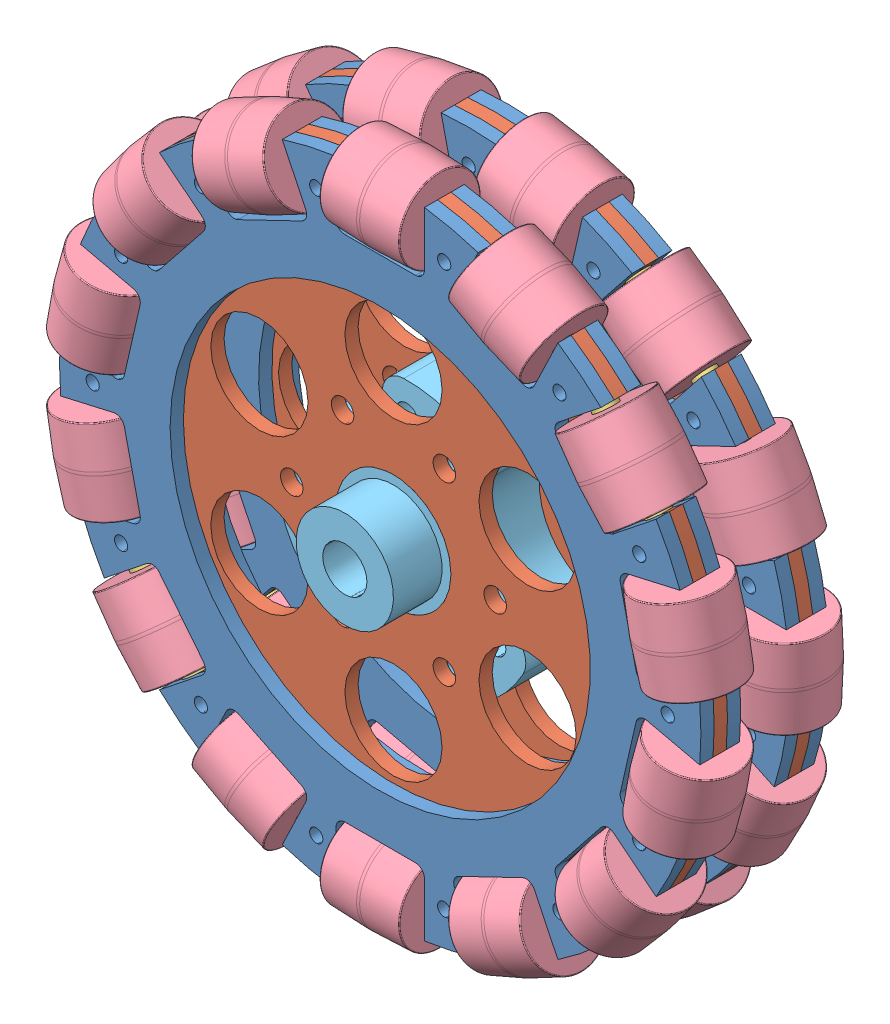
SolidWorks assembly 150mm全向轮-0320, configuration 默认. Lengths in mm.
Overall size (192.95 192.95 43.78).
63 component instances, 5 part files, 26 mates.
Components (placement in the parent):
- VJ_150全向轮外壁-0320-1: VJ_150全向轮外壁-0320 [默认] at (-10.4986 6.27 143.5) size (145 143.61 3)
- VJ_150全向轮内壁-0320-1: VJ_150全向轮内壁-0320 [默认] at (-10.4986 6.27 146.5) size (145 143.61 3)
- VJ_150全向轮外壁-0320-2: VJ_150全向轮外壁-0320 [默认] at (-10.4986 6.27 152.5) x (0.900969 0.433884 0) z (0 0 -1) size (145 143.61 3)
- VJ_150全向轮滚柱-0320-1: VJ_150全向轮滚柱-0320 [默认] at (-72.9604 32.8351 148) x (0.531534 -0.121319 -0.838304) z (-0.222521 -0.974928 0) size (5 5 24)
- VJ_150全向轮滚柱-0320-2: VJ_150全向轮滚柱-0320 [默认] at (-78.3009 3.1032 148) x (0.531534 0.121319 -0.838304) z (0.222521 -0.974928 0) size (5 5 24)
- VJ_150全向轮滚柱-0320-3: VJ_150全向轮滚柱-0320 [默认] at (-70.2123 -26.0015 148) x (0.426257 0.339929 -0.838304) z (0.62349 -0.781831 0) size (5 5 24)
- VJ_150全向轮滚柱-0320-4: VJ_150全向轮滚柱-0320 [默认] at (-50.2967 -48.7145 148) x (0.236555 0.491211 -0.838304) z (0.900969 -0.433884 0) size (5 5 24)
- VJ_150全向轮滚柱-0320-5: VJ_150全向轮滚柱-0320 [默认] at (-22.4986 -60.537 148) x (0 0.545203 -0.838304) z (1 0 0) size (5 5 24)
- VJ_150全向轮滚柱-0320-6: VJ_150全向轮滚柱-0320 [默认] at (7.6763 -59.1277 148) x (-0.236555 0.491211 -0.838304) z (0.900969 0.433884 0) size (5 5 24)
- VJ_150全向轮滚柱-0320-7: VJ_150全向轮滚柱-0320 [默认] at (34.2514 -44.7655 148) x (-0.426257 0.339929 -0.838304) z (0.62349 0.781831 0) size (5 5 24)
- VJ_150全向轮滚柱-0320-8: VJ_150全向轮滚柱-0320 [默认] at (51.9632 -20.2951 148) x (-0.531534 0.121319 -0.838304) z (0.222521 0.974928 0) size (5 5 24)
- VJ_150全向轮滚柱-0320-9: VJ_150全向轮滚柱-0320 [默认] at (57.3037 9.4368 148) x (-0.531534 -0.121319 -0.838304) z (-0.222521 0.974928 0) size (5 5 24)
- VJ_150全向轮滚柱-0320-10: VJ_150全向轮滚柱-0320 [默认] at (49.2151 38.5415 148) x (-0.426257 -0.339929 -0.838304) z (-0.62349 0.781831 0) size (5 5 24)
- VJ_150全向轮滚柱-0320-11: VJ_150全向轮滚柱-0320 [默认] at (29.2995 61.2544 148) x (-0.236555 -0.491211 -0.838304) z (-0.900969 0.433884 0) size (5 5 24)
- VJ_150全向轮滚柱-0320-12: VJ_150全向轮滚柱-0320 [默认] at (1.5014 73.077 148) x (0 -0.545203 -0.838304) z (-1 0 0) size (5 5 24)
- VJ_150全向轮滚柱-0320-13: VJ_150全向轮滚柱-0320 [默认] at (-28.6734 71.6676 148) x (0.236555 -0.491211 -0.838304) z (-0.900969 -0.433884 0) size (5 5 24)
- VJ_150全向轮滚柱-0320-14: VJ_150全向轮滚柱-0320 [默认] at (-55.2485 57.3055 148) x (0.426257 -0.339929 -0.838304) z (-0.62349 -0.781831 0) size (5 5 24)
- VJ_150全向轮小轮-0320-1: VJ_150全向轮小轮-0320 [默认] at (-75.6306 -8.596 148) x (0.950484 0.216942 -0.222521) z (0.222521 -0.974928 0) size (18.99 18.99 18)
- VJ_150全向轮小轮-0320-2: VJ_150全向轮小轮-0320 [默认] at (-62.7304 -35.3835 148) x (0.762229 0.607858 -0.222521) z (0.62349 -0.781831 0) size (18.99 18.99 18)
- VJ_150全向轮小轮-0320-3: VJ_150全向轮小轮-0320 [默认] at (-39.4851 -53.9211 148) x (0.423005 0.87838 -0.222521) z (0.900969 -0.433884 0) size (18.99 18.99 18)
- VJ_150全向轮小轮-0320-4: VJ_150全向轮小轮-0320 [默认] at (-10.4986 -60.537 148) x (0 0.974928 -0.222521) z (1 0 0) size (18.99 18.99 18)
- VJ_150全向轮小轮-0320-5: VJ_150全向轮小轮-0320 [默认] at (18.4879 -53.9211 148) x (-0.423005 0.87838 -0.222521) z (0.900969 0.433884 0) size (18.99 18.99 18)
- VJ_150全向轮小轮-0320-6: VJ_150全向轮小轮-0320 [默认] at (41.7333 -35.3835 148) x (-0.762229 0.607858 -0.222521) z (0.62349 0.781831 0) size (18.99 18.99 18)
- VJ_150全向轮小轮-0320-7: VJ_150全向轮小轮-0320 [默认] at (54.6335 -8.596 148) x (-0.950484 0.216942 -0.222521) z (0.222521 0.974928 0) size (18.99 18.99 18)
- VJ_150全向轮小轮-0320-8: VJ_150全向轮小轮-0320 [默认] at (54.6335 21.136 148) x (-0.950484 -0.216942 -0.222521) z (-0.222521 0.974928 0) size (18.99 18.99 18)
- VJ_150全向轮小轮-0320-9: VJ_150全向轮小轮-0320 [默认] at (41.7333 47.9235 148) x (-0.762229 -0.607858 -0.222521) z (-0.62349 0.781831 0) size (18.99 18.99 18)
- VJ_150全向轮小轮-0320-10: VJ_150全向轮小轮-0320 [默认] at (18.4879 66.461 148) x (-0.423005 -0.87838 -0.222521) z (-0.900969 0.433884 0) size (18.99 18.99 18)
- VJ_150全向轮小轮-0320-11: VJ_150全向轮小轮-0320 [默认] at (-10.4986 73.077 148) x (0 -0.974928 -0.222521) z (-1 0 0) size (18.99 18.99 18)
- VJ_150全向轮小轮-0320-12: VJ_150全向轮小轮-0320 [默认] at (-39.4851 66.461 148) x (0.423005 -0.87838 -0.222521) z (-0.900969 -0.433884 0) size (18.99 18.99 18)
- VJ_150全向轮小轮-0320-13: VJ_150全向轮小轮-0320 [默认] at (-62.7304 47.9235 148) x (0.762229 -0.607858 -0.222521) z (-0.62349 -0.781831 0) size (18.99 18.99 18)
- VJ_150全向轮小轮-0320-14: VJ_150全向轮小轮-0320 [默认] at (-75.6306 21.136 148) x (0.950484 -0.216942 -0.222521) z (-0.222521 -0.974928 0) size (18.99 18.99 18)
- VJ_150全向轮联轴-0320-1: VJ_150全向轮联轴-0320 [默认] at (-10.4986 6.27 129.5) x (0.965926 -0.258819 0) z (0 0 1) size (58.57 53.07 35)
- VJ_150全向轮外壁-0320-3: VJ_150全向轮外壁-0320 [默认] at (-10.4986 6.27 132.5) x (-0.433884 0.900969 0) z (0 0 -1) size (145 143.61 3)
- VJ_150全向轮内壁-0320-2: VJ_150全向轮内壁-0320 [默认] at (-10.4986 6.27 126.5) x (0 1 0) z (0 0 1) size (145 143.61 3)
- VJ_150全向轮外壁-0320-4: VJ_150全向轮外壁-0320 [默认] at (-10.4986 6.27 123.5) x (0 1 0) z (0 0 1) size (145 143.61 3)
- VJ_150全向轮滚柱-0320-15: VJ_150全向轮滚柱-0320 [默认] at (-37.0637 68.7318 128) x (-0.216942 0.950484 -0.222521) z (0.974928 0.222521 0) size (5 5 24)
- VJ_150全向轮滚柱-0320-16: VJ_150全向轮滚柱-0320 [默认] at (-61.5341 51.02 128) x (-0.607858 0.762229 -0.222521) z (0.781831 0.62349 0) size (5 5 24)
- VJ_150全向轮滚柱-0320-17: VJ_150全向轮滚柱-0320 [默认] at (-75.8962 24.4448 128) x (-0.87838 0.423005 -0.222521) z (0.433884 0.900969 0) size (5 5 24)
- VJ_150全向轮滚柱-0320-18: VJ_150全向轮滚柱-0320 [默认] at (-77.3056 -5.73 128) x (-0.974928 0 -0.222521) z (0 1 0) size (5 5 24)
- VJ_150全向轮滚柱-0320-19: VJ_150全向轮滚柱-0320 [默认] at (-65.483 -33.5281 128) x (-0.87838 -0.423005 -0.222521) z (-0.433884 0.900969 0) size (5 5 24)
- VJ_150全向轮滚柱-0320-20: VJ_150全向轮滚柱-0320 [默认] at (-42.7701 -53.4437 128) x (-0.607858 -0.762229 -0.222521) z (-0.781831 0.62349 0) size (5 5 24)
- VJ_150全向轮滚柱-0320-21: VJ_150全向轮滚柱-0320 [默认] at (-13.6654 -61.5323 128) x (-0.216942 -0.950484 -0.222521) z (-0.974928 0.222521 0) size (5 5 24)
- VJ_150全向轮滚柱-0320-22: VJ_150全向轮滚柱-0320 [默认] at (16.0665 -56.1918 128) x (0.216942 -0.950484 -0.222521) z (-0.974928 -0.222521 0) size (5 5 24)
- VJ_150全向轮滚柱-0320-23: VJ_150全向轮滚柱-0320 [默认] at (40.5369 -38.48 128) x (0.607858 -0.762229 -0.222521) z (-0.781831 -0.62349 0) size (5 5 24)
- VJ_150全向轮滚柱-0320-24: VJ_150全向轮滚柱-0320 [默认] at (54.8991 -11.9049 128) x (0.87838 -0.423005 -0.222521) z (-0.433884 -0.900969 0) size (5 5 24)
- VJ_150全向轮滚柱-0320-25: VJ_150全向轮滚柱-0320 [默认] at (56.3084 18.27 128) x (0.974928 0 -0.222521) z (0 -1 0) size (5 5 24)
- VJ_150全向轮滚柱-0320-26: VJ_150全向轮滚柱-0320 [默认] at (44.4859 46.0681 128) x (0.87838 0.423005 -0.222521) z (0.433884 -0.900969 0) size (5 5 24)
- VJ_150全向轮滚柱-0320-27: VJ_150全向轮滚柱-0320 [默认] at (21.7729 65.9837 128) x (0.607858 0.762229 -0.222521) z (0.781831 -0.62349 0) size (5 5 24)
- VJ_150全向轮滚柱-0320-28: VJ_150全向轮滚柱-0320 [默认] at (-7.3318 74.0723 128) x (0.216942 0.950484 -0.222521) z (0.974928 -0.222521 0) size (5 5 24)
- VJ_150全向轮小轮-0320-15: VJ_150全向轮小轮-0320 [默认] at (-25.3645 71.402 128) x (-0.217508 0.952966 -0.211058) z (0.974928 0.222521 0) size (18.99 18.99 18)
- VJ_150全向轮小轮-0320-16: VJ_150全向轮小轮-0320 [默认] at (-52.1521 58.5018 128) x (-0.609445 0.76422 -0.211058) z (0.781831 0.62349 0) size (18.99 18.99 18)
- VJ_150全向轮小轮-0320-17: VJ_150全向轮小轮-0320 [默认] at (-70.6896 35.2565 128) x (-0.880673 0.42411 -0.211058) z (0.433884 0.900969 0) size (18.99 18.99 18)
- VJ_150全向轮小轮-0320-18: VJ_150全向轮小轮-0320 [默认] at (-77.3056 6.27 128) x (-0.977474 0 -0.211058) z (0 1 0) size (18.99 18.99 18)
- VJ_150全向轮小轮-0320-19: VJ_150全向轮小轮-0320 [默认] at (-70.6896 -22.7165 128) x (-0.880673 -0.42411 -0.211058) z (-0.433884 0.900969 0) size (18.99 18.99 18)
- VJ_150全向轮小轮-0320-20: VJ_150全向轮小轮-0320 [默认] at (-52.1521 -45.9619 128) x (-0.609445 -0.76422 -0.211058) z (-0.781831 0.62349 0) size (18.99 18.99 18)
- VJ_150全向轮小轮-0320-21: VJ_150全向轮小轮-0320 [默认] at (-25.3645 -58.8621 128) x (-0.217508 -0.952966 -0.211058) z (-0.974928 0.222521 0) size (18.99 18.99 18)
- VJ_150全向轮小轮-0320-22: VJ_150全向轮小轮-0320 [默认] at (4.3674 -58.8621 128) x (0.217508 -0.952966 -0.211058) z (-0.974928 -0.222521 0) size (18.99 18.99 18)
- VJ_150全向轮小轮-0320-23: VJ_150全向轮小轮-0320 [默认] at (31.1549 -45.9619 128) x (0.609445 -0.76422 -0.211058) z (-0.781831 -0.62349 0) size (18.99 18.99 18)
- VJ_150全向轮小轮-0320-24: VJ_150全向轮小轮-0320 [默认] at (49.6925 -22.7165 128) x (0.880673 -0.42411 -0.211058) z (-0.433884 -0.900969 0) size (18.99 18.99 18)
- VJ_150全向轮小轮-0320-25: VJ_150全向轮小轮-0320 [默认] at (56.3084 6.27 128) x (0.977474 0 -0.211058) z (0 -1 0) size (18.99 18.99 18)
- VJ_150全向轮小轮-0320-26: VJ_150全向轮小轮-0320 [默认] at (49.6925 35.2565 128) x (0.880673 0.42411 -0.211058) z (0.433884 -0.900969 0) size (18.99 18.99 18)
- VJ_150全向轮小轮-0320-27: VJ_150全向轮小轮-0320 [默认] at (31.1549 58.5018 128) x (0.609445 0.76422 -0.211058) z (0.781831 -0.62349 0) size (18.99 18.99 18)
- VJ_150全向轮小轮-0320-28: VJ_150全向轮小轮-0320 [默认] at (4.3674 71.402 128) x (0.217508 0.952966 -0.211058) z (0.974928 -0.222521 0) size (18.99 18.99 18)
Mates (geometry in assembly coordinates):
- 同心1: concentric: circle of VJ_150全向轮内壁-0320-1; circle of VJ_150全向轮外壁-0320-2
- 同心2: concentric: circle of VJ_150全向轮外壁-0320-1; cylinder of VJ_150全向轮内壁-0320-1 through (-10.4986 6.27 146.5) axis (0 0 1) radius 13
- 重合1: coincident: plane of VJ_150全向轮外壁-0320-1 through (-72.6739 68.6437 146.5) normal (-0.62349 -0.781831 0); plane of VJ_150全向轮内壁-0320-1 through (-72.6739 68.6437 149.5) normal (-0.62349 -0.781831 0)
- 重合3: coincident: plane of VJ_150全向轮外壁-0320-1 through (-10.4986 6.27 146.5) normal (0 0 1); plane of VJ_150全向轮内壁-0320-1 through (-10.4986 6.27 146.5) normal (0 0 -1)
- 重合5: coincident: plane of VJ_150全向轮内壁-0320-1 through (-10.4986 6.27 149.5) normal (0 0 1); plane of VJ_150全向轮外壁-0320-2 through (-10.4986 6.27 149.5) normal (0 0 -1)
- 重合6: coincident: plane of VJ_150全向轮外壁-0320-1 through (-72.6739 68.6437 146.5) normal (-0.62349 -0.781831 0); plane of VJ_150全向轮外壁-0320-2 through (-72.6739 68.6437 149.5) normal (-0.62349 -0.781831 0)
- 同心3: concentric: cylinder of VJ_150全向轮外壁-0320-1 through (-72.9604 32.8351 148) axis (-0.222521 -0.974928 0) radius 2.5; cylinder of VJ_150全向轮滚柱-0320-1 through (-78.3009 9.4368 148) axis (0.222521 0.974928 0) radius 2.5
- 重合7: coincident: plane of VJ_150全向轮内壁-0320-1 through (-78.3009 9.4368 148) normal (0.222521 0.974928 0); plane of VJ_150全向轮滚柱-0320-1 through (-78.3009 9.4368 148) normal (-0.222521 -0.974928 0)
- 同心4: concentric: cylinder of VJ_150全向轮滚柱-0320-2 through (-72.9604 -20.2951 148) axis (-0.222521 0.974928 0) radius 2.5; cylinder of VJ_150全向轮小轮-0320-1 through (-77.6333 0.1784 148) axis (0.222521 -0.974928 0) radius 2.5
- 距离1: distance = 1 mm: plane of VJ_150全向轮小轮-0320-1 through (-77.6333 0.1784 148) normal (-0.222521 0.974928 0); plane of VJ_150全向轮内壁-0320-1 through (-98.03 -3.4513 149.5) normal (0.222521 -0.974928 0)
- 同心6: concentric: cylinder of VJ_150全向轮内壁-0320-1 through (1.0014 26.1886 146.5) axis (0 0 1) radius 2.55; cylinder of VJ_150全向轮联轴-0320-1 through (1.0014 26.1886 146.5) axis (0 0 -1) radius 2.5
- 重合9: coincident: plane of VJ_150全向轮内壁-0320-1 through (-10.4986 6.27 146.5) normal (0 0 -1); plane of VJ_150全向轮联轴-0320-1 through (-10.4986 6.27 146.5) normal (0 0 1)
- 同心7: concentric: circle of VJ_150全向轮外壁-0320-3; cylinder of VJ_150全向轮内壁-0320-2 through (-10.4986 6.27 126.5) axis (0 0 1) radius 13
- 同心8: concentric: cylinder of VJ_150全向轮内壁-0320-2 through (-10.4986 6.27 126.5) axis (0 0 1) radius 13; cylinder of VJ_150全向轮外壁-0320-4 through (-10.4986 6.27 123.5) axis (0 0 1) radius 47.5
- 重合10: coincident: plane of VJ_150全向轮外壁-0320-3 through (-10.4986 6.27 129.5) normal (0 0 -1); plane of VJ_150全向轮内壁-0320-2 through (-10.4986 6.27 129.5) normal (0 0 1)
- 重合11: coincident: plane of VJ_150全向轮外壁-0320-3 through (-72.8723 68.4453 129.5) normal (0.781831 0.62349 0); plane of VJ_150全向轮内壁-0320-2 through (-72.8723 68.4453 129.5) normal (0.781831 0.62349 0)
- 重合12: coincident: plane of VJ_150全向轮内壁-0320-2 through (-10.4986 6.27 126.5) normal (0 0 -1); plane of VJ_150全向轮外壁-0320-4 through (-10.4986 6.27 126.5) normal (0 0 1)
- 重合13: coincident: plane of VJ_150全向轮内壁-0320-2 through (-72.8723 68.4453 129.5) normal (0.781831 0.62349 0); plane of VJ_150全向轮外壁-0320-4 through (-72.8723 68.4453 126.5) normal (0.781831 0.62349 0)
- 同心9: concentric: cylinder of VJ_150全向轮外壁-0320-3 through (-37.0637 68.7318 128) axis (0.974928 0.222521 0) radius 2.5; cylinder of VJ_150全向轮滚柱-0320-15 through (-13.6654 74.0723 128) axis (-0.974928 -0.222521 0) radius 2.5
- 重合14: coincident: plane of VJ_150全向轮内壁-0320-2 through (-13.6654 74.0723 128) normal (-0.974928 -0.222521 0); plane of VJ_150全向轮滚柱-0320-15 through (-13.6654 74.0723 128) normal (0.974928 0.222521 0)
- 同心10: concentric: cylinder of VJ_150全向轮滚柱-0320-15 through (-13.6654 74.0723 128) axis (-0.974928 -0.222521 0) radius 2.5; cylinder of VJ_150全向轮小轮-0320-15 through (-34.1389 69.3993 128) axis (0.974928 0.222521 0) radius 2.5
- 距离2: distance = 1 mm: plane of VJ_150全向轮小轮-0320-15 through (-34.1389 69.3993 128) normal (-0.974928 -0.222521 0); plane of VJ_150全向轮内壁-0320-2 through (-39.7184 89.351 129.5) normal (0.974928 0.222521 0)
- 重合16: coincident: plane of VJ_150全向轮联轴-0320-1 through (-10.4986 6.27 129.5) normal (0 0 -1); plane of VJ_150全向轮内壁-0320-2 through (-10.4986 6.27 129.5) normal (0 0 1)
- 同心12: concentric: circle of VJ_150全向轮联轴-0320-1; circle of VJ_150全向轮内壁-0320-2
- 同心13: concentric: circle of VJ_150全向轮联轴-0320-1; cylinder of VJ_150全向轮内壁-0320-2 through (-10.4986 6.27 126.5) axis (0 0 1) radius 13
- 同心14: concentric: circle of VJ_150全向轮内壁-0320-1; circle of VJ_150全向轮联轴-0320-1
